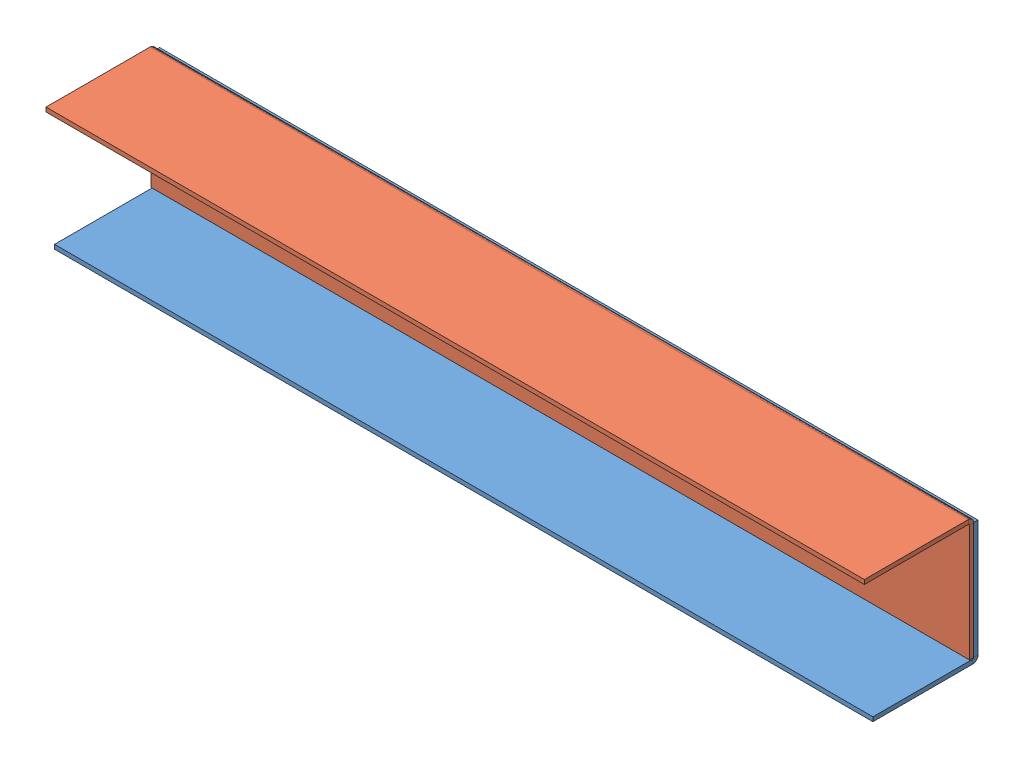
SolidWorks assembly wheel well, configuration Default. Lengths in mm.
Overall size (609.6 94.9 84.64).
2 component instances, 2 part files, 3 mates.
Components (placement in the parent):
- one side-2: one side [Default] at (-462.6454 416.4223 41.8495) size (609.6 90.99 78.29)
- other side-2: other side [Default] at (-462.6454 489.6851 45.0245) x (-1 0 0) z (0 0 1) size (609.6 90.99 81.46)
Mates (geometry in assembly coordinates):
- Coincident2: coincident: plane of one side-2 through (-462.6454 416.4223 41.8495) normal (0 0 1); plane of other side-2 through (-462.6454 489.6851 41.8495) normal (0 0 -1)
- Coincident3: coincident: line of one side-2 through (-767.4454 408.7226 41.8495) axis (1 0 0); line of other side-2 through (-767.4454 408.7226 41.8495) axis (1 0 0)
- Coincident4: coincident aligned: line of one side-2 through (-157.8454 408.7226 41.8495) axis (0 1 0); line of other side-2 through (-157.8454 408.7226 41.8495) axis (0 1 0)
